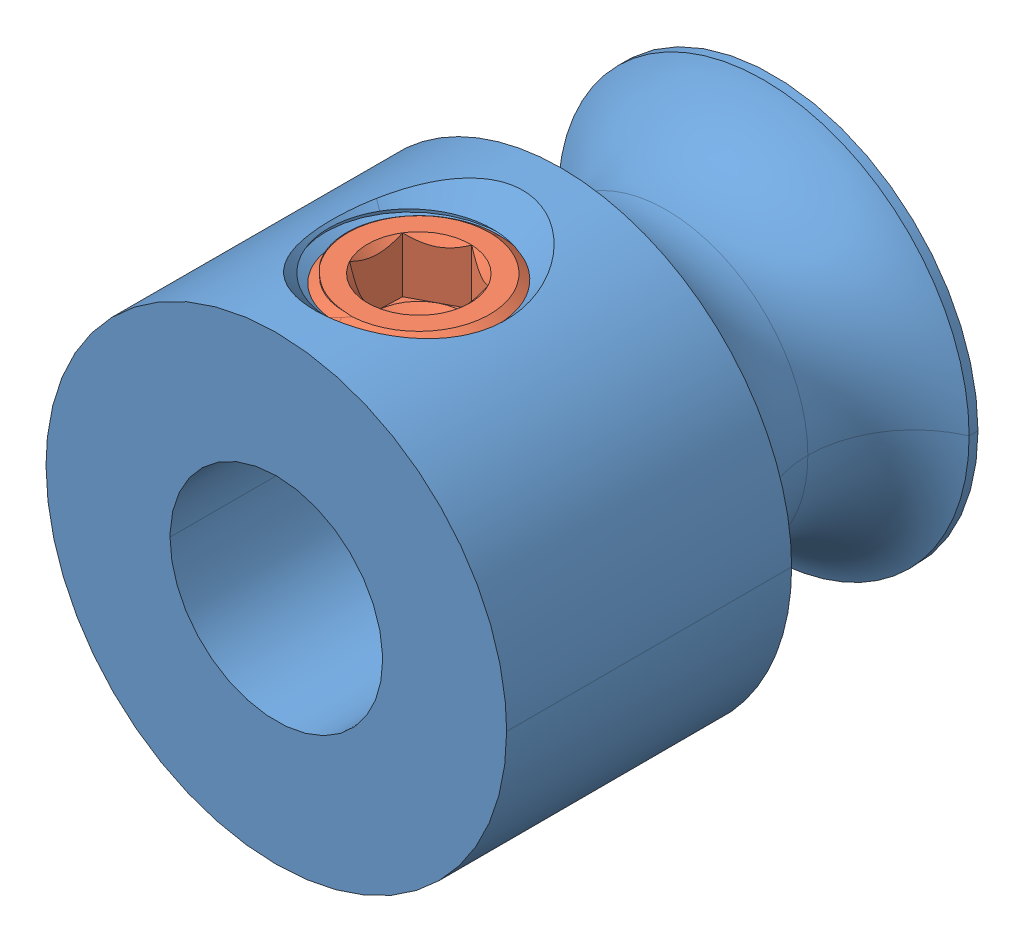
SolidWorks assembly 3401-0006-0008 assembly, configuration Default. Lengths in mm.
Overall size (13 13.01 14).
3 component instances, 2 part files, 0 mates.
Components (placement in the parent):
- 3401-0006-0008 assembly.STEP-1: 3401-0006-0008 assembly.STEP [Default] at origin size (13 13.01 14)
  - 3401-0006-0008.STEP-1: 3401-0006-0008.STEP [Default] at (-39.6905 29.1567 8.1355) size (13 13.01 14)
  - 2806-0005-0004_91390A117.STEP-1: 2806-0005-0004_91390A117.STEP [Default] at (-39.6905 33.4996 4.1145) x (0.999377 0 0.035289) z (0 1 0) size (5.01 5.01 4.01)
